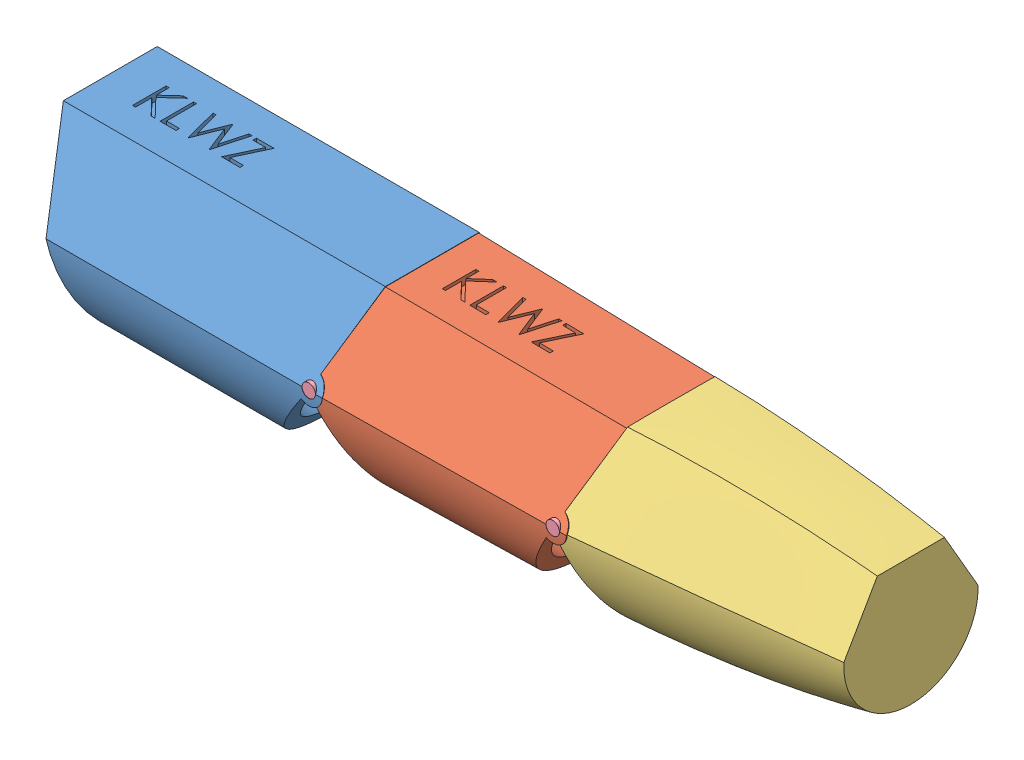
SolidWorks assembly Index,Ring Finger-KLWZ, configuration Default. Lengths in mm.
Overall size (75.8 17.12 17.91).
11 component instances, 6 part files, 17 mates.
Components (placement in the parent):
- Index,Ring Bottom-KLWZ-1: Index,Ring Bottom-KLWZ [Default] at (-10.8929 30.6765 25.4038) size (30.48 17.11 17.82)
- Index,Ring Middle-KLWZ-1: Index,Ring Middle-KLWZ [Default] at (16.7849 30.6765 25.4038) size (26.67 16.95 17.91)
- Index,Ring Tip-KLWZ-1: Index,Ring Tip-KLWZ [Default] at (39.5019 30.2308 25.4038) size (26.68 17.04 17.2)
- Hinge Pin-KLWZ-1: Hinge Pin-KLWZ [Default] at (16.7849 22.9775 32.7698) x (1 0 0) z (0 -1 0) size (1.27 1.52 1.27)
- Hinge Pin-KLWZ-2: Hinge Pin-KLWZ [Default] at (16.7849 22.9775 16.5138) x (1 0 0) z (0 -1 0) size (1.27 1.52 1.27)
- Hinge Pin-KLWZ-3: Hinge Pin-KLWZ [Default] at (39.5019 22.8618 16.8939) x (1 0 0) z (0 -1 0) size (1.27 1.52 1.27)
- Hinge Pin-KLWZ-4: Hinge Pin-KLWZ [Default] at (39.5019 22.8618 32.3896) x (1 0 0) z (0 -1 0) size (1.27 1.52 1.27)
- Hinge 3-KLWZ-1: Hinge 3-KLWZ [Default] at (-6.7857 12.0092 22.8683) x (0.998734 -0.050311 0) z (0 0 1) size (2.55 0.58 2.54) (flexible)
  - Hinge 3-KLWZ-1: Hinge 3-KLWZ [Default] at (1.5197 1.8887 1.2654) size (1.52 0.51 2.54)
  - Hinge 3-KLWZ-2: Hinge 3-KLWZ [Default] at (1.5197 1.8887 3.8054) x (-0.998734 -0.050311 0) z (0 0 -1) size (1.52 0.51 2.54)
  - Hinge 3 Pin-KLWZ-1: Hinge 3 Pin-KLWZ [Default] at (1.5197 1.8887 3.8054) x (1 0 0) z (0 1 0) size (0.25 2.54 0.25)
Mates (geometry in assembly coordinates):
- Coincident1: coincident aligned: circle of Index,Ring Middle-KLWZ-1; circle of Index,Ring Bottom-KLWZ-1
- Coincident2: coincident anti-aligned: circle of Index,Ring Middle-KLWZ-1; circle of Index,Ring Bottom-KLWZ-1
- Coincident3: coincident aligned: circle of Index,Ring Tip-KLWZ-1; circle of Index,Ring Middle-KLWZ-1
- Coincident5: coincident anti-aligned: circle of Index,Ring Middle-KLWZ-1; circle of Index,Ring Tip-KLWZ-1
- LimitAngle1: limit planar angle = 0 rad anti-aligned: plane of Index,Ring Bottom-KLWZ-1 through (19.5871 30.6765 16.4993) normal (0.939693 -0.34202 0); plane of Index,Ring Middle-KLWZ-1 through (20.3468 32.7637 16.4993) normal (-0.939693 0.34202 0)
- LimitAngle3: limit planar angle = 0 rad anti-aligned: plane of Index,Ring Middle-KLWZ-1 through (42.1849 30.2331 16.4993) normal (0.939693 -0.34202 0); plane of Index,Ring Tip-KLWZ-1 through (43.3246 33.3645 16.8247) normal (-0.939693 0.34202 0)
- Concentric1: concentric anti-aligned: cylinder of Index,Ring Bottom-KLWZ-1 through (16.7849 22.9775 16.4993) axis (0 0 1) radius 0.635; cylinder of Hinge Pin-KLWZ-1 through (16.7849 22.9775 34.2938) axis (0 0 -1) radius 0.635
- Coincident8: coincident: point of Index,Ring Bottom-KLWZ-1; circle of Hinge Pin-KLWZ-1
- Concentric2: concentric anti-aligned: cylinder of Index,Ring Bottom-KLWZ-1 through (16.7849 22.9775 16.4993) axis (0 0 1) radius 0.635; cylinder of Hinge Pin-KLWZ-2 through (16.7849 22.9775 18.0378) axis (0 0 -1) radius 0.635
- Coincident9: coincident: point of Index,Ring Bottom-KLWZ-1; circle of Hinge Pin-KLWZ-2
- Concentric3: concentric anti-aligned: cylinder of Index,Ring Middle-KLWZ-1 through (39.5019 22.8618 16.4993) axis (0 0 1) radius 0.635; cylinder of Hinge Pin-KLWZ-3 through (39.5019 22.8618 18.4179) axis (0 0 -1) radius 0.635
- Coincident10: coincident: point of Index,Ring Middle-KLWZ-1; circle of Hinge Pin-KLWZ-3
- Concentric4: concentric anti-aligned: cylinder of Index,Ring Middle-KLWZ-1 through (39.5019 22.8618 16.4993) axis (0 0 1) radius 0.635; cylinder of Hinge Pin-KLWZ-4 through (39.5019 22.8618 33.9136) axis (0 0 -1) radius 0.635
- Coincident11: coincident: point of Index,Ring Middle-KLWZ-1; circle of Hinge Pin-KLWZ-4
- Coincident12: coincident anti-aligned: plane of Index,Ring Bottom-KLWZ-1 through (-10.8929 14.073 25.4038) normal (0 -1 0); plane of Hinge 3-KLWZ-1/Hinge 3-KLWZ-2 through (-5.1729 14.073 24.1338) normal (0 1 0)
- Coincident13: coincident anti-aligned: line of Index,Ring Bottom-KLWZ-1 through (-3.9029 14.073 26.6738) axis (0 0 -1); line of Hinge 3-KLWZ-1/Hinge 3-KLWZ-2 through (-3.9029 14.073 24.1338) axis (0 0 1)
- Coincident14: coincident: point of Index,Ring Bottom-KLWZ-1; point of Hinge 3-KLWZ-1/Hinge 3-KLWZ-2
